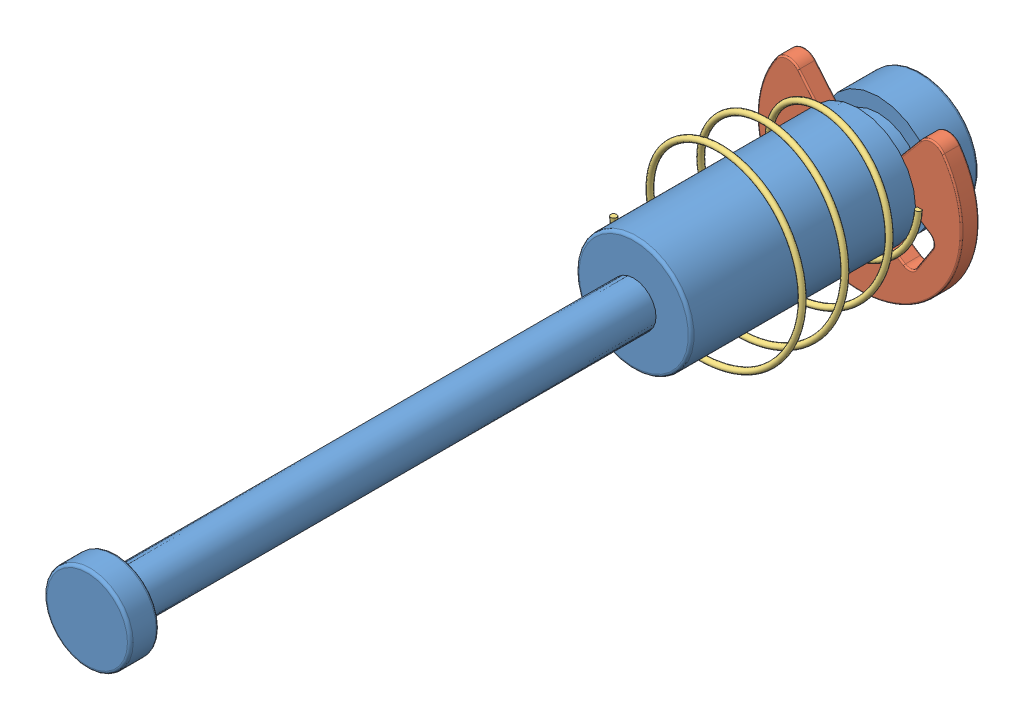
SolidWorks assembly Shaft Assem, configuration Default. Lengths in mm.
Overall size (7.1 6.76 29).
3 component instances, 3 part files, 5 mates.
Components (placement in the parent):
- Shaft-1: Shaft [Default] at origin size (4 4 29)
- Circlip-1: Circlip [Default] at (0 0 -8.45) size (7.1 5.79 0.6)
- Spring-1: Spring [Default] at (0 0 -2.3) x (-1 0 0) z (0 0 -1) size (6.3 6.5 5.85)
Mates (geometry in assembly coordinates):
- Coincident2: coordinate: point of Shaft-1; point of assembly
- Distance1: distance = 0.05 mm: plane of Shaft-1 through (0 2 -8.5) normal (0 0 1); plane of Circlip-1 through (0 0 -8.45) normal (0 0 -1)
- Coincident4: coincident: plane of Shaft-1 through (0 0 0) normal (1 0 0); plane of Spring-1 through (0 0 -2.3) normal (-1 0 0)
- Coincident5: coincident: plane of Shaft-1 through (0 0 0) normal (0 1 0); plane of Spring-1
- Distance2: distance = 2.3 mm: plane of Spring-1 through (0 0 -2.3) normal (0 0 -1); plane of Shaft-1 through (0 0 0) normal (0 0 1)
